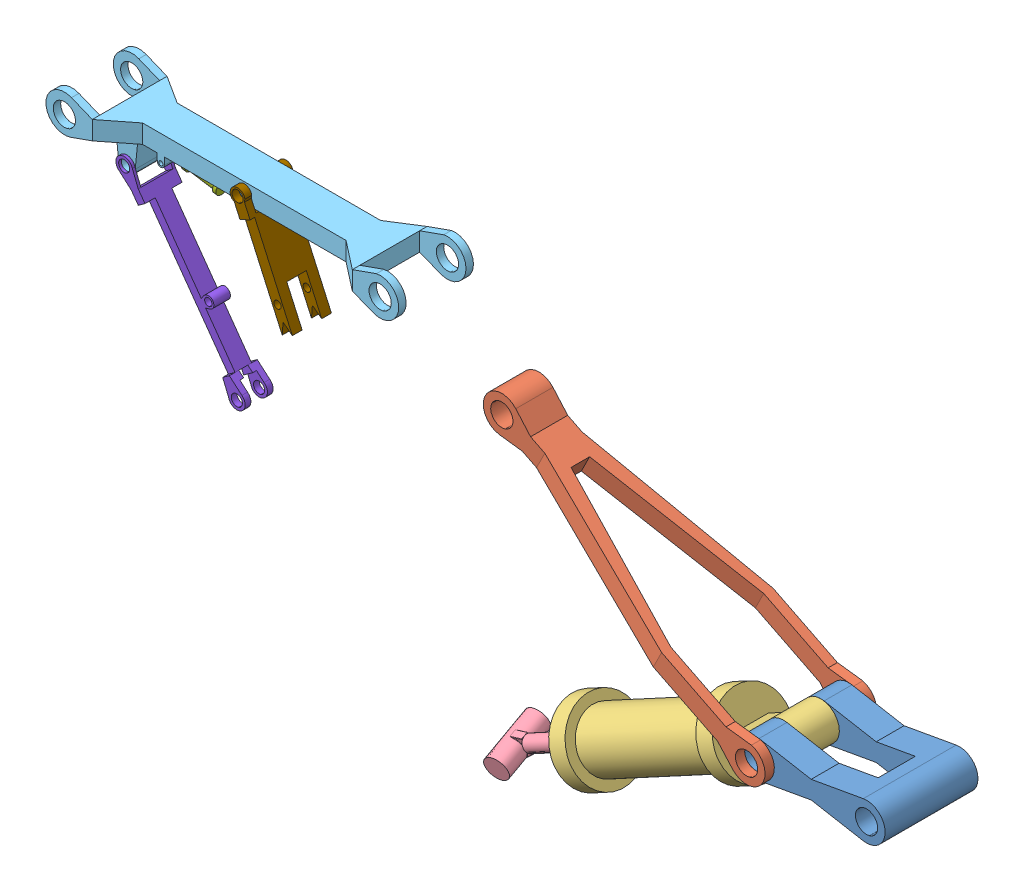
SolidWorks assembly Landing gear assem, configuration Default. Lengths in mm.
Overall size (2360.81 1001.36 327.92).
9 component instances, 9 part files, 18 mates.
Components (placement in the parent):
- 2nd hinge-1: 2nd hinge [Default] at (27.7134 -9.4062 -133.2335) size (398.13 100 250)
- hinge-1: hinge [Default] at (-500.834 181.959 -158.2335) x (0.894235 -0.447598 0) z (0 0 1) size (949.73 102.54 300)
- nasos-1: nasos [Default] at (-462.4986 -193.593 -8.2335) x (0 0 1) z (0.87994 0.475085 0) size (200 200 700)
- nasos 2-1: nasos 2 [Default] at (-853.4629 -404.677 -8.2335) x (0.152486 -0.28243 0.947091) z (0.87994 0.475085 0) size (140 80 701)
- hinge2-1: hinge2 [Default] at (-1659.3036 459.0553 -262.5732) size (949.73 170.92 201.22)
- nasos 2 malenkyi-1: nasos 2 malenkyi [Default] at (-1461.0708 347.8979 -91.0876) x (0 0 -1) z (-0.987968 0.154661 0) size (26.25 15 131.44)
- nasos malenkyi-1: nasos malenkyi [Default] at (-1789.0904 399.2477 -91.0877) x (0 0 -1) z (-0.987968 0.154661 0) size (37.5 37.5 131.25)
- hinge 3-1: hinge 3 [Default] at (-1834.313 158.5771 -141.0877) x (0.582325 -0.812956 0) z (0 0 1) size (545 64.79 100)
- hinge 4-1: hinge 4 [Default] at (-1609.2381 347.9017 -156.0877) x (0.410682 -0.911779 0) z (0 0 1) size (315.9 67.59 130)
Mates (geometry in assembly coordinates):
- Concentric1: concentric anti-aligned: cylinder of 2nd hinge-1 through (-121.3529 -9.4062 116.7665) axis (0 0 -1) radius 30; cylinder of hinge-1 through (-121.3529 -9.4062 -158.2335) axis (0 0 1) radius 30
- Coincident1: coincident anti-aligned: plane of 2nd hinge-1 through (27.7134 -9.4062 116.7665) normal (0 0 1); plane of hinge-1 through (-484.2385 -134.2719 116.7665) normal (0 0 -1)
- Concentric2: concentric anti-aligned: cylinder of 2nd hinge-1 through (-121.3529 -9.4062 116.7665) axis (0 0 -1) radius 30; cylinder of nasos-1 through (-121.3529 -9.4062 -108.2335) axis (0 0 1) radius 30
- Coincident2: coincident anti-aligned: plane of 2nd hinge-1 through (133.0768 -134.4062 41.7665) normal (0 0 -1); plane of nasos-1 through (-731.5478 -247.3955 41.7665) normal (0 0 1)
- Concentric3: concentric anti-aligned: cylinder of nasos-1 through (-649.3168 -294.4573 -8.2335) axis (0.87994 0.475085 0) radius 24; cylinder of nasos 2-1 through (-360.6965 -138.6294 -8.2335) axis (-0.87994 -0.475085 0) radius 20
- LimitDistance2: limit distance = 1 mm anti-aligned: plane of nasos 2-1 through (-298.2208 -104.8984 -8.2335) normal (0.87994 0.475085 0); plane of nasos-1 through (-297.3408 -104.4233 -8.2335) normal (-0.87994 -0.475085 0)
- LimitDistance3: limit distance = 328 mm anti-aligned: plane of nasos 2-1 through (-360.6965 -138.6294 -8.2335) normal (-0.87994 -0.475085 0); plane of nasos-1 through (-649.3168 -294.4573 -8.2335) normal (0.87994 0.475085 0)
- Concentric4: concentric anti-aligned: cylinder of hinge2-1 through (-1884.3036 414.1529 -176.704) axis (0 0 1) radius 5.625; cylinder of nasos malenkyi-1 through (-1884.3036 414.1529 -72.3377) axis (0 0 -1) radius 5.625
- Coincident3: coincident anti-aligned: plane of hinge2-1 through (-1912.7548 435.9012 -81.7127) normal (0 0 -1); plane of nasos malenkyi-1 through (-1761.5613 410.2117 -81.7127) normal (0 0 1)
- Concentric5: concentric anti-aligned: cylinder of nasos 2 malenkyi-1 through (-1777.3305 397.4068 -91.0877) axis (0.987968 -0.154661 0) radius 3.75; cylinder of nasos malenkyi-1 through (-1773.1573 396.7535 -91.0877) axis (-0.987968 0.154661 0) radius 4.5
- LimitDistance4: limit distance = 57.4635 mm anti-aligned: plane of nasos 2 malenkyi-1 through (-1790.4828 399.4657 -91.0877) normal (-0.987968 0.154661 0); plane of nasos malenkyi-1 through (-1847.2549 408.3531 -91.0877) normal (0.987968 -0.154661 0)
- LimitDistance5: limit distance = 4.224 mm anti-aligned: plane of nasos 2 malenkyi-1 through (-1777.3305 397.4068 -91.0877) normal (0.987968 -0.154661 0); plane of nasos malenkyi-1 through (-1773.1573 396.7535 -91.0877) normal (-0.987968 0.154661 0)
- Concentric7: concentric anti-aligned: cylinder of hinge2-1 through (-1979.4309 361.9 -198.2346) axis (0 0 1) radius 15; cylinder of hinge 3-1 through (-1979.4309 361.9 -41.0877) axis (0 0 -1) radius 15
- Coincident6: coincident anti-aligned: plane of hinge2-1 through (-2009.177 333.6988 -48.2346) normal (0 0 1); plane of hinge 3-1 through (-1986.3695 295.426 -48.2346) normal (0 0 -1)
- Concentric8: concentric aligned: cylinder of hinge2-1 through (-1659.3036 459.0553 -186.1508) axis (0 0 1) radius 15; cylinder of hinge 4-1 through (-1659.3036 459.0553 -156.0877) axis (0 0 1) radius 15
- Coincident7: coincident anti-aligned: plane of hinge2-1 through (-1659.4882 -516.3012 -137.6497) normal (0 0 -1); plane of hinge 4-1 through (-1746.5744 372.788 -137.6497) normal (0 0 1)
- Coincident8: coincident aligned: circle of nasos 2 malenkyi-1; cylinder of hinge 4-1 through (-1666.1841 380.0074 -187.3946) axis (0 0 1) radius 5.625
- Coincident9: coincident aligned: plane of nasos 2 malenkyi-1 through (-1666.1841 380.0074 -77.9627) normal (0 0 1); plane of hinge 4-1 through (-1588.3312 301.4852 -77.9627) normal (0 0 1)
